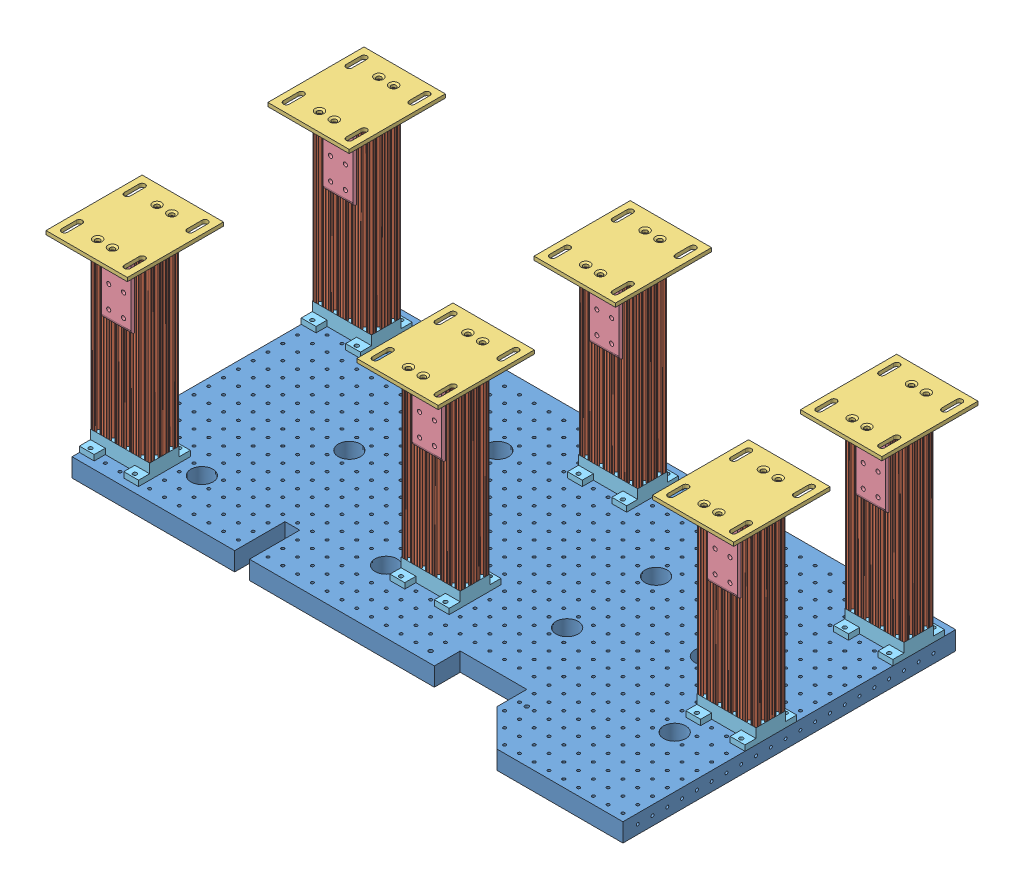
SolidWorks assembly breadboard 1 assembly, configuration Default. Lengths in mm.
Overall size (2698.7 750.49 660.98).
43 component instances, 5 part files, 18 mates.
Components (placement in the parent):
- Breadboard1-1: Breadboard1 [Default] at (-194.6573 17.0814 91.1131) size (1016 31.75 641.73)
- breadboard support leg assembly-1: breadboard support leg assembly [Default] at (-182.8187 304.0452 -389.5924) x (0 0 -1) z (0 1 0) size (165.1 139.7 339.72)
  - 8020-2040 leg for breadboard support-1: 8020-2040 leg for breadboard support [Default] at (-48.9055 -77.0614 78.1612) size (50.8 101.6 307.98)
  - 8020-2387-DEFAULT-1: 8020-2387-DEFAULT [Default] at (-34.9863 -22.6888 91.8816) x (0 1 0) z (-1 0 0) size (139.7 133.35 165.1)
    - 8020-2387-DEFAULT_238708-1: 8020-2387-DEFAULT_238708 [Default] at (-67.1549 7.3704 27.8119) size (139.7 6.35 165.1)
    - 8020-2387-DEFAULT_238509-1: 8020-2387-DEFAULT_238509 [Default] at (9.1264 0.0214 49.7635) x (0 0 1) z (-1 0 0) size (50.8 127 50.8)
    - 8020-2387-DEFAULT_238509-2: 8020-2387-DEFAULT_238509 [Default] at (-41.6736 0.0214 -46.9187) x (0 0 -1) z (1 0 0) size (50.8 127 50.8)
  - breadboard support leg top bracket-1: breadboard support leg top bracket [Default] at (-61.6055 -89.7614 -229.8138) x (0 1 0) z (-1 0 0) size (101.6 25.4 88.9)
- breadboard support leg assembly-3: breadboard support leg assembly [Default] at (352.3041 304.0452 -317.1813) x (0 0 1) z (0 1 0) size (165.1 139.7 339.72)
  - 8020-2040 leg for breadboard support-1: 8020-2040 leg for breadboard support [Default] at (-48.9055 -77.0614 78.1612) size (50.8 101.6 307.98)
  - 8020-2387-DEFAULT-1: 8020-2387-DEFAULT [Default] at (-34.9863 -22.6888 91.8816) x (0 1 0) z (-1 0 0) size (139.7 133.35 165.1)
    - 8020-2387-DEFAULT_238708-1: 8020-2387-DEFAULT_238708 [Default] at (-67.1549 7.3704 27.8119) size (139.7 6.35 165.1)
    - 8020-2387-DEFAULT_238509-1: 8020-2387-DEFAULT_238509 [Default] at (9.1264 0.0214 49.7635) x (0 0 1) z (-1 0 0) size (50.8 127 50.8)
    - 8020-2387-DEFAULT_238509-2: 8020-2387-DEFAULT_238509 [Default] at (-41.6736 0.0214 -46.9187) x (0 0 -1) z (1 0 0) size (50.8 127 50.8)
  - breadboard support leg top bracket-1: breadboard support leg top bracket [Default] at (-61.6055 -89.7614 -229.8138) x (0 1 0) z (-1 0 0) size (101.6 25.4 88.9)
- breadboard support leg assembly-4: breadboard support leg assembly [Default] at (274.3813 304.0452 -135.5924) x (0 0 -1) z (0 1 0) size (165.1 139.7 339.72)
  - 8020-2040 leg for breadboard support-1: 8020-2040 leg for breadboard support [Default] at (-48.9055 -77.0614 78.1612) size (50.8 101.6 307.98)
  - 8020-2387-DEFAULT-1: 8020-2387-DEFAULT [Default] at (-34.9863 -22.6888 91.8816) x (0 1 0) z (-1 0 0) size (139.7 133.35 165.1)
    - 8020-2387-DEFAULT_238708-1: 8020-2387-DEFAULT_238708 [Default] at (-67.1549 7.3704 27.8119) size (139.7 6.35 165.1)
    - 8020-2387-DEFAULT_238509-1: 8020-2387-DEFAULT_238509 [Default] at (9.1264 0.0214 49.7635) x (0 0 1) z (-1 0 0) size (50.8 127 50.8)
    - 8020-2387-DEFAULT_238509-2: 8020-2387-DEFAULT_238509 [Default] at (-41.6736 0.0214 -46.9187) x (0 0 -1) z (1 0 0) size (50.8 127 50.8)
  - breadboard support leg top bracket-1: breadboard support leg top bracket [Default] at (-61.6055 -89.7614 -229.8138) x (0 1 0) z (-1 0 0) size (101.6 25.4 88.9)
- breadboard support leg assembly-5: breadboard support leg assembly [Default] at (-104.8959 304.0452 -12.3813) x (0 0 1) z (0 1 0) size (165.1 139.7 339.72)
  - 8020-2040 leg for breadboard support-1: 8020-2040 leg for breadboard support [Default] at (-48.9055 -77.0614 78.1612) size (50.8 101.6 307.98)
  - 8020-2387-DEFAULT-1: 8020-2387-DEFAULT [Default] at (-34.9863 -22.6888 91.8816) x (0 1 0) z (-1 0 0) size (139.7 133.35 165.1)
    - 8020-2387-DEFAULT_238708-1: 8020-2387-DEFAULT_238708 [Default] at (-67.1549 7.3704 27.8119) size (139.7 6.35 165.1)
    - 8020-2387-DEFAULT_238509-1: 8020-2387-DEFAULT_238509 [Default] at (9.1264 0.0214 49.7635) x (0 0 1) z (-1 0 0) size (50.8 127 50.8)
    - 8020-2387-DEFAULT_238509-2: 8020-2387-DEFAULT_238509 [Default] at (-41.6736 0.0214 -46.9187) x (0 0 -1) z (1 0 0) size (50.8 127 50.8)
  - breadboard support leg top bracket-1: breadboard support leg top bracket [Default] at (-61.6055 -89.7614 -229.8138) x (0 1 0) z (-1 0 0) size (101.6 25.4 88.9)
- breadboard support leg assembly-6: breadboard support leg assembly [Default] at (-640.0187 304.0452 -8.5924) x (0 0 -1) z (0 1 0) size (165.1 139.7 339.72)
  - 8020-2040 leg for breadboard support-1: 8020-2040 leg for breadboard support [Default] at (-48.9055 -77.0614 78.1612) size (50.8 101.6 307.98)
  - 8020-2387-DEFAULT-1: 8020-2387-DEFAULT [Default] at (-34.9863 -22.6888 91.8816) x (0 1 0) z (-1 0 0) size (139.7 133.35 165.1)
    - 8020-2387-DEFAULT_238708-1: 8020-2387-DEFAULT_238708 [Default] at (-67.1549 7.3704 27.8119) size (139.7 6.35 165.1)
    - 8020-2387-DEFAULT_238509-1: 8020-2387-DEFAULT_238509 [Default] at (9.1264 0.0214 49.7635) x (0 0 1) z (-1 0 0) size (50.8 127 50.8)
    - 8020-2387-DEFAULT_238509-2: 8020-2387-DEFAULT_238509 [Default] at (-41.6736 0.0214 -46.9187) x (0 0 -1) z (1 0 0) size (50.8 127 50.8)
  - breadboard support leg top bracket-1: breadboard support leg top bracket [Default] at (-61.6055 -89.7614 -229.8138) x (0 1 0) z (-1 0 0) size (101.6 25.4 88.9)
- breadboard support leg assembly-7: breadboard support leg assembly [Default] at (-640.0187 304.0452 -389.5924) x (0 0 -1) z (0 1 0) size (165.1 139.7 339.72)
  - 8020-2040 leg for breadboard support-1: 8020-2040 leg for breadboard support [Default] at (-48.9055 -77.0614 78.1612) size (50.8 101.6 307.98)
  - 8020-2387-DEFAULT-1: 8020-2387-DEFAULT [Default] at (-34.9863 -22.6888 91.8816) x (0 1 0) z (-1 0 0) size (139.7 133.35 165.1)
    - 8020-2387-DEFAULT_238708-1: 8020-2387-DEFAULT_238708 [Default] at (-67.1549 7.3704 27.8119) size (139.7 6.35 165.1)
    - 8020-2387-DEFAULT_238509-1: 8020-2387-DEFAULT_238509 [Default] at (9.1264 0.0214 49.7635) x (0 0 1) z (-1 0 0) size (50.8 127 50.8)
    - 8020-2387-DEFAULT_238509-2: 8020-2387-DEFAULT_238509 [Default] at (-41.6736 0.0214 -46.9187) x (0 0 -1) z (1 0 0) size (50.8 127 50.8)
  - breadboard support leg top bracket-1: breadboard support leg top bracket [Default] at (-61.6055 -89.7614 -229.8138) x (0 1 0) z (-1 0 0) size (101.6 25.4 88.9)
Mates (geometry in assembly coordinates):
- Coincident1: coincident anti-aligned: plane of Breadboard1-1 through (-194.6573 48.8314 -416.8869) normal (0 1 0); plane of breadboard support leg assembly-1/breadboard support leg top bracket-1 through (-93.0573 48.8314 -378.7869) normal (0 -1 0)
- Parallel2: parallel aligned: plane of Breadboard1-1 through (-651.8573 17.0814 -416.8869) normal (-1 0 0); plane of breadboard support leg assembly-1/breadboard support leg top bracket-1 through (-194.6573 48.8314 -327.9869) normal (-1 0 0)
- Coincident8: coincident anti-aligned: plane of Breadboard1-1 through (-194.6573 48.8314 -416.8869) normal (0 1 0); plane of breadboard support leg assembly-5/breadboard support leg top bracket-1 through (-194.6573 48.8314 -23.1869) normal (0 -1 0)
- Parallel4: parallel anti-aligned: plane of Breadboard1-1 through (-194.6573 48.8314 -416.8869) normal (0 0 -1); plane of breadboard support leg assembly-5/breadboard support leg top bracket-1 through (-93.0573 58.3564 -4.1369) normal (0 0 1)
- Coincident13: coincident anti-aligned: plane of Breadboard1-1 through (-194.6573 48.8314 -416.8869) normal (0 1 0); plane of breadboard support leg assembly-4/breadboard support leg top bracket-1 through (364.1427 48.8314 -124.7869) normal (0 -1 0)
- Coincident16: coincident anti-aligned: plane of Breadboard1-1 through (-194.6573 48.8314 -416.8869) normal (0 1 0); plane of breadboard support leg assembly-3/breadboard support leg top bracket-1 through (262.5427 48.8314 -327.9869) normal (0 -1 0)
- Coincident17: coincident aligned: plane of Breadboard1-1 through (364.1427 48.8314 91.1131) normal (1 0 0); plane of breadboard support leg assembly-3/breadboard support leg top bracket-1 through (364.1427 48.8314 -378.7869) normal (1 0 0)
- Concentric2: concentric anti-aligned: circle of Breadboard1-1; circle of breadboard support leg assembly-3/breadboard support leg top bracket-1
- Concentric4: concentric anti-aligned: circle of breadboard support leg assembly-5/breadboard support leg top bracket-1; circle of Breadboard1-1
- Concentric6: concentric anti-aligned: circle of Breadboard1-1; circle of breadboard support leg assembly-1/breadboard support leg top bracket-1
- Concentric7: concentric anti-aligned: circle of breadboard support leg assembly-4/breadboard support leg top bracket-1; circle of Breadboard1-1
- Parallel5: parallel aligned: plane of Breadboard1-1 through (364.1427 48.8314 91.1131) normal (1 0 0); plane of breadboard support leg assembly-4/breadboard support leg top bracket-1 through (364.1427 48.8314 -73.9869) normal (1 0 0)
- Coincident19: coincident anti-aligned: plane of Breadboard1-1 through (-194.6573 48.8314 -416.8869) normal (0 1 0); plane of breadboard support leg assembly-6/breadboard support leg top bracket-1 through (-550.2573 48.8314 2.2131) normal (0 -1 0)
- Concentric8: concentric anti-aligned: circle of Breadboard1-1; circle of breadboard support leg assembly-6/breadboard support leg top bracket-1
- Parallel6: parallel aligned: plane of Breadboard1-1 through (-651.8573 17.0814 -416.8869) normal (-1 0 0); plane of breadboard support leg assembly-6/breadboard support leg top bracket-1 through (-651.8573 48.8314 53.0131) normal (-1 0 0)
- Coincident21: coincident anti-aligned: plane of Breadboard1-1 through (-194.6573 48.8314 -416.8869) normal (0 1 0); plane of breadboard support leg assembly-7/breadboard support leg top bracket-1 through (-550.2573 48.8314 -378.7869) normal (0 -1 0)
- Concentric9: concentric anti-aligned: circle of Breadboard1-1; circle of breadboard support leg assembly-7/breadboard support leg top bracket-1
- Parallel7: parallel aligned: plane of Breadboard1-1 through (-651.8573 17.0814 -416.8869) normal (-1 0 0); plane of breadboard support leg assembly-7/breadboard support leg top bracket-1 through (-651.8573 48.8314 -327.9869) normal (-1 0 0)
